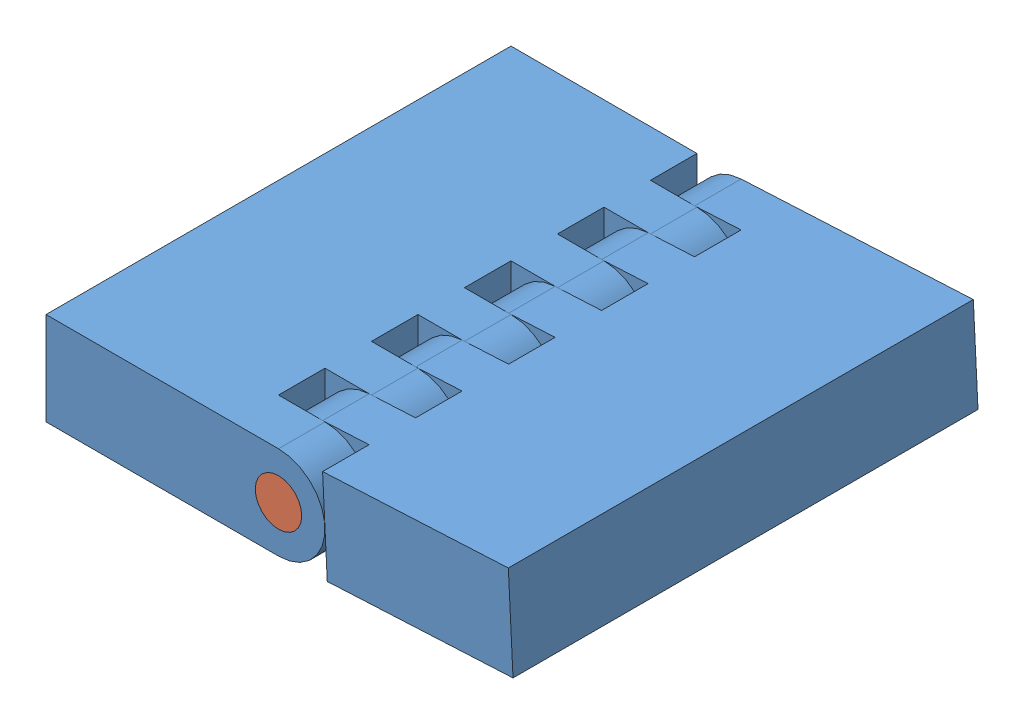
SolidWorks assembly Hinge 3-KLWZ, configuration Default. Lengths in mm.
Overall size (2.55 0.58 2.54).
3 component instances, 2 part files, 3 mates.
Components (placement in the parent):
- Hinge 3-KLWZ-1: Hinge 3-KLWZ [Default] at (1.5197 1.8887 1.2654) size (1.52 0.51 2.54)
- Hinge 3-KLWZ-2: Hinge 3-KLWZ [Default] at (1.5197 1.8887 3.8054) x (-0.998734 -0.050311 0) z (0 0 -1) size (1.52 0.51 2.54)
- Hinge 3 Pin-KLWZ-1: Hinge 3 Pin-KLWZ [Default] at (1.5197 1.8887 3.8054) x (1 0 0) z (0 1 0) size (0.25 2.54 0.25)
Mates (geometry in assembly coordinates):
- Coincident1: coincident anti-aligned: circle of Hinge 3-KLWZ-1; circle of Hinge 3-KLWZ-2
- Concentric1: concentric anti-aligned: cylinder of Hinge 3-KLWZ-1 through (1.5197 1.8887 3.8054) axis (0 0 -1) radius 0.127; cylinder of Hinge 3 Pin-KLWZ-1 through (1.5197 1.8887 1.2654) axis (0 0 1) radius 0.127
- Coincident2: coincident anti-aligned: circle of Hinge 3-KLWZ-1; circle of Hinge 3 Pin-KLWZ-1
